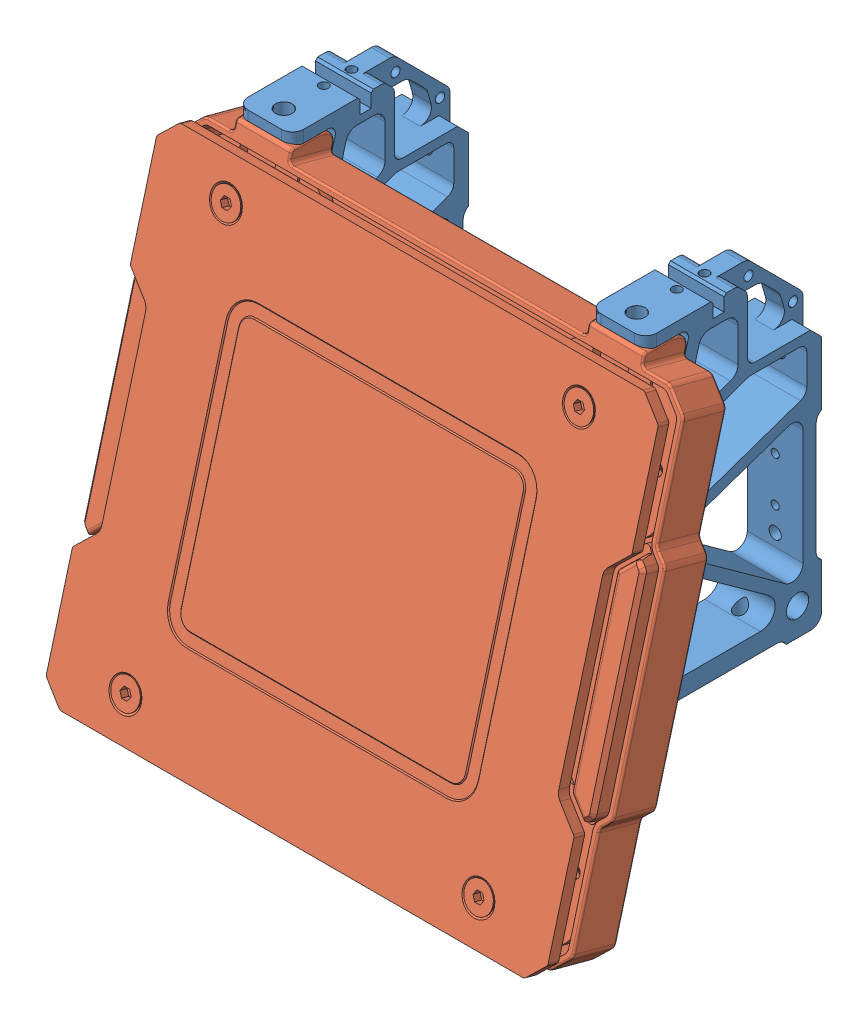
SolidWorks assembly 装甲板模块, configuration 默认. Lengths in mm.
Overall size (141 144.21 108.31).
3 component instances, 2 part files, 9 mates.
Components (placement in the parent):
- RM2019裁判系统支撑架AH02-1: RM2019裁判系统支撑架AH02 [默认] at (-47.5 -90 11.1154) x (1 0 0) z (0 0.258819 0.965926) size (15 130.97 68.39)
- RoboMaster 装甲模块 AM02 2020-1: RoboMaster 装甲模块 AM02 2020 [默认] at (-45.0044 -124.3917 48.1387) x (0 0.258819 0.965926) z (-1 0 0) size (19 129.97 141)
- RM2019裁判系统支撑架AH02-2: RM2019裁判系统支撑架AH02 [默认] at (47.5 -90 11.1154) x (1 0 0) z (0 0.258819 0.965926) size (15 130.97 68.39)
Mates (geometry in assembly coordinates):
- 对称1: symmetric aligned: plane of RM2019裁判系统支撑架AH02-1 through (-40 -90 11.1154) normal (1 0 0); plane of RM2019裁判系统支撑架AH02-2 through (40 -90 11.1154) normal (-1 0 0)
- 平行1: parallel aligned: plane of RM2019裁判系统支撑架AH02-1 through (-40 -90 11.1154) normal (1 0 0)
- 重合1: coincident aligned: plane of RM2019裁判系统支撑架AH02-1 through (-5.3179 0 -13) normal (0 1 0); plane of RM2019裁判系统支撑架AH02-2 through (89.6821 0 -13) normal (0 1 0)
- 重合2: coincident aligned: plane of RM2019裁判系统支撑架AH02-1 through (-40 -3.0667 -12.1783) normal (0 0.258819 0.965926); plane of RM2019裁判系统支撑架AH02-2 through (55 -3.0667 -12.1783) normal (0 0.258819 0.965926)
- 重合3: coincident aligned: plane of RM2019裁判系统支撑架AH02-1 through (-5.3179 0 -13) normal (0 1 0)
- 重合4: coincident aligned: plane of RM2019裁判系统支撑架AH02-1 through (-69.1193 -3.2 0) normal (0 0 1)
- 重合5: coincident anti-aligned: plane of RM2019裁判系统支撑架AH02-1 through (-69.1193 -3.2 -12.1426) normal (0 -1 0); plane of RoboMaster 装甲模块 AM02 2020-1 through (-40 -3.2 -12.1907) normal (0 1 0)
- 同心1: concentric anti-aligned: cylinder of RM2019裁判系统支撑架AH02-1 through (-47.5 6.8 -5.1346) axis (0 -1 0) radius 2.25; cylinder of RoboMaster 装甲模块 AM02 2020-1 through (-47.5 -3.2 -5.1346) axis (0 1 0) radius 1.65
- 同心2: concentric anti-aligned: cylinder of RoboMaster 装甲模块 AM02 2020-1 through (47.5 -3.2 -5.1346) axis (0 1 0) radius 1.65; cylinder of RM2019裁判系统支撑架AH02-2 through (47.5 6.8 -5.1346) axis (0 -1 0) radius 2.25
